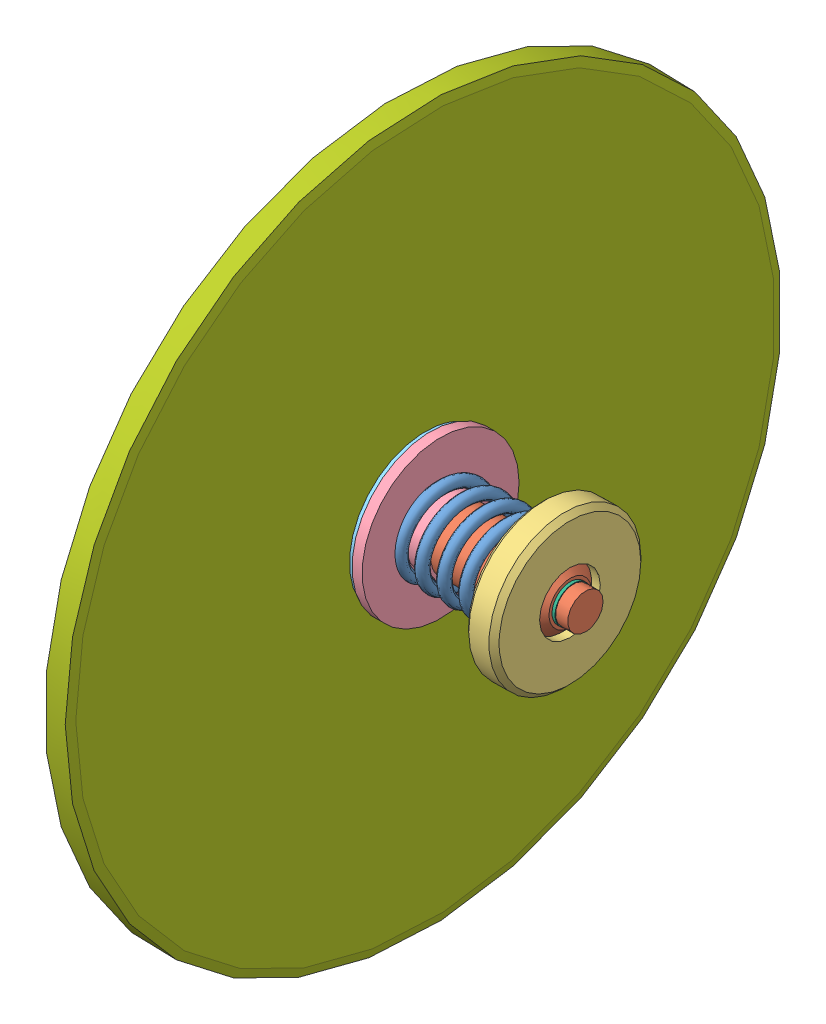
SolidWorks assembly mufta, configuration Полный. Lengths in mm.
Overall size (51 141.4 141.4).
7 component instances, 7 part files, 18 mates.
Components (placement in the parent):
- prushina-1: prushina [Полный] at (-61.987 0 0) x (0 0.715642 0.698468) z (1 0 0) size (18.92 18.98 26.11)
- val5-1: val5 [Полный] at (-73.2912 0 0) x (0 -0.973244 -0.229772) z (1 0 0) size (15 15 51)
- vt1-1: vt1 [Полный] at (-41.3486 0 0) x (0 -1 0) z (0 0 1) size (30 6 30)
- vt2-1: vt2 [Полный] at (-56.8912 0 0) x (0 1 0) z (0 0 1) size (31 6 31)
- disk-1: disk [Полный] at (-63.8912 0 0) x (0 0.969939 -0.24335) z (1 0 0) size (30 30 1)
- подш2-1: подш2 [Полный] at (-35.2912 0 0) x (0 1 0) z (1 0 0) size (7.2 7.2 2)
- z8-1: z8 [Полный] at (-63.8912 0 0) x (0 1 0) z (0 0 1) size (141.4 4.9 141.4)
Mates (geometry in assembly coordinates):
- Концентричный1: concentric anti-aligned: line of prushina-1 through (9.2405 -61.987 0) axis (0 1 0); cylinder of val5-1 through (-35.2912 0 0) axis (-1 0 0) radius 6
- Концентричный2: concentric aligned: cylinder of val5-1 through (-35.2912 0 0) axis (-1 0 0) radius 6; cylinder of vt1-1 through (-41.3486 0 0) axis (-1 0 0) radius 6
- Концентричный3: concentric anti-aligned: cylinder of val5-1 through (-35.2912 0 0) axis (-1 0 0) radius 6; cylinder of vt2-1 through (-56.8912 0 0) axis (1 0 0) radius 6
- Концентричный4: concentric aligned: cylinder of val5-1 through (-35.2912 0 0) axis (-1 0 0) radius 6; cylinder of disk-1 through (-62.8912 0 0) axis (-1 0 0) radius 6
- Совпадение3: coincident anti-aligned: plane of vt2-1 through (-62.8912 6 0) normal (-1 0 0); plane of disk-1 through (-62.8912 0 0) normal (1 0 0)
- Концентричный6: concentric anti-aligned: cylinder of val5-1 through (-32.2912 0 0) axis (-1 0 0) radius 3.5; cylinder of подш2-1 through (-35.2912 0 0) axis (1 0 0) radius 1
- Совпадение15: coincident anti-aligned: plane of disk-1 through (-63.8912 0 0) normal (-1 0 0); plane of z8-1 through (-63.8912 0 0) normal (1 0 0)
- Совпадение22: coincident aligned: plane of vt1-1 through (-41.3486 0 0) normal (0 0 1)
- Совпадение23: coincident aligned: plane of vt2-1 through (-56.8912 0 0) normal (0 0 1)
- Совпадение24: coincident aligned: plane of подш2-1 through (-35.2912 0 0) normal (0 0 1)
- Совпадение25: coincident aligned: plane of z8-1 through (-63.8912 0 0) normal (0 0 1)
- Совпадение30: coincident: line of z8-1 through (-68.7912 0 0) axis (1 0 0)
- Совпадение31: coincident anti-aligned: plane of prushina-1 through (-60.8912 0 0) normal (-1 0 0); plane of vt2-1 through (-60.8912 15.5 0) normal (1 0 0)
- Совпадение32: coincident anti-aligned: plane of prushina-1 through (-41.3486 0 0) normal (1 0 0); plane of vt1-1 through (-41.3486 -15 0) normal (-1 0 0)
- Совпадение33: coincident anti-aligned: plane of prushina-1 through (-61.987 0 0) normal (0 0 -1)
- Совпадение36: coincident anti-aligned: plane of val5-1 through (-68.7912 0 0) normal (1 0 0); plane of z8-1 through (-68.7912 70.7 0) normal (-1 0 0)
- Концентричный7: concentric anti-aligned: cylinder of val5-1 through (-35.2912 0 0) axis (-1 0 0) radius 6; cylinder of z8-1 through (-68.7912 0 0) axis (1 0 0) radius 6
- Совпадение37: coincident anti-aligned: plane of val5-1 through (-35.2912 0 0) normal (1 0 0); plane of подш2-1 through (-35.2912 0 0) normal (-1 0 0)
